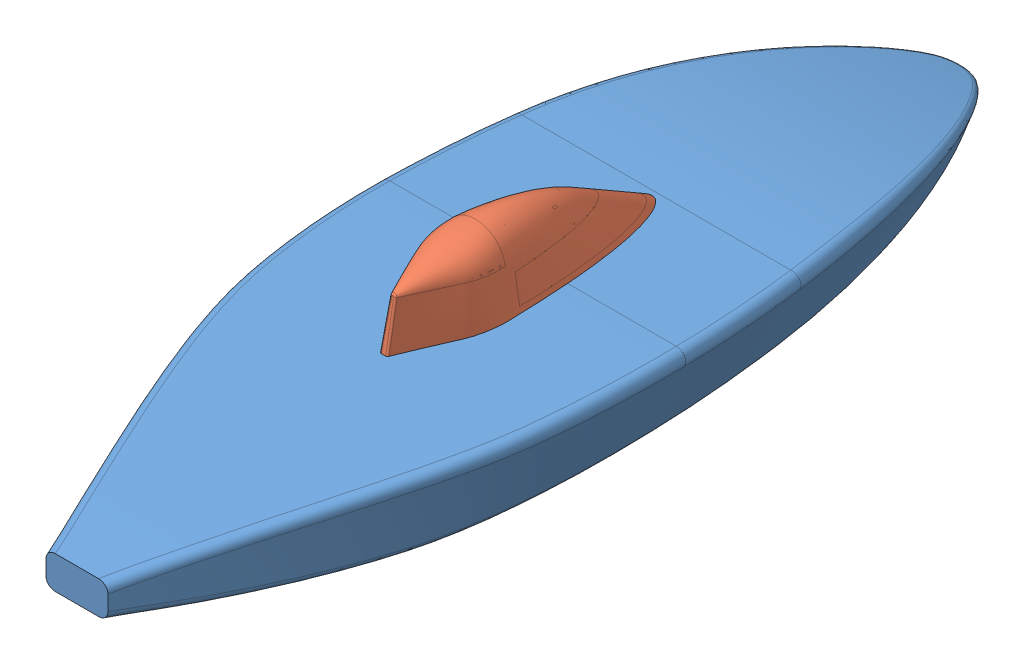
SolidWorks assembly Assem13, configuration Default. Lengths in mm.
Overall size (2147.64 1145.19 4962.59).
2 component instances, 2 part files, 0 mates.
Components (placement in the parent):
- Alain Wide Body (Double Naca New Canopy, 5 inch high, high nose)-1: Alain Wide Body (Double Naca New Canopy, 5 inch high, high nose) [Default] at (681.5959 1560.6954 5126.16) size (2147.64 927.55 4962.59)
- windshileld4-1: windshileld4 [Default] at (513.1662 1539.2798 2909.0331) x (0 0 1) z (-1 0 0) size (1688.13 400.44 575.69)
